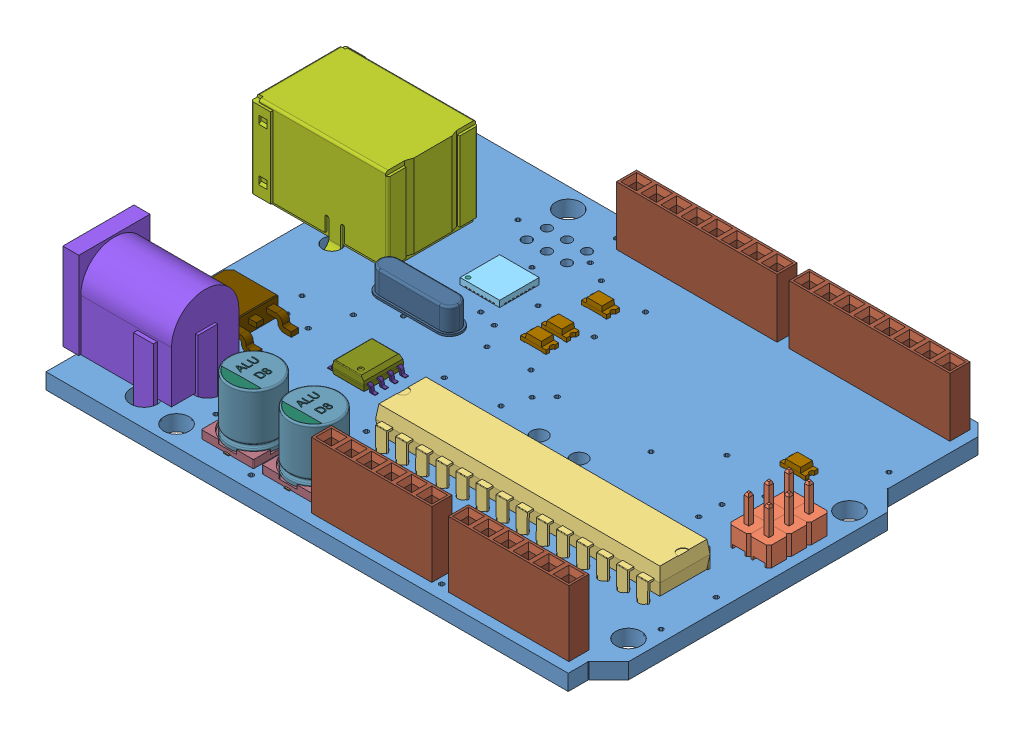
SolidWorks assembly Final, configuration Predeterminado. Lengths in mm.
Overall size (74.75 15.43 53.34).
32 component instances, 18 part files, 18 mates.
Components (placement in the parent):
- PCB_Final-1: PCB_Final [Default] at origin size (68.58 2 53.34)
- Header Vertical 2.54mm Pitch2-1: Header Vertical 2.54mm Pitch2 [Header 6 Way] at (62.2731 2 -29.1415) size (5.08 8.88 7.62)
- IC DIP 28-1: IC DIP 28 [Default] at (51.4233 4.3498 -16.4837) x (0 0.005002 0.999987) z (-1 0 0) size (7.87 6.22 35.94)
- User Library-QFN32 (FTDI)-1: User Library-QFN32 (FTDI) [Default] at (19.2089 2.05 -38.1588) x (-1 0 0) z (0 1 0) size (5 5 0.85)
  - User Library-QFN32 (FTDI)_Anschl_X_FCsse_1-1: User Library-QFN32 (FTDI)_Anschl_X_FCsse_1 [Default] x (0 -1 0) z (0 0 1) size (5 5 0.2)
  - User Library-QFN32 (FTDI)_K_X_F6rper_1-1: User Library-QFN32 (FTDI)_K_X_F6rper_1 [Default] at origin size (5 5 0.8)
  - User Library-QFN32 (FTDI)_Beschriftung_1-1: User Library-QFN32 (FTDI)_Beschriftung_1 [Default] at origin size (0.51 0.51 0.05)
- User Library-67068-0000-molex-1: User Library-67068-0000-molex [Default] at (-6.1546 2 -38.0545) x (0.002421 0 0.999997) z (-0.999997 0 0.002421) size (14.9 15.43 17)
- User Library-dc range - dc connector[4840_2201]-1: User Library-dc range - dc connector[4840_2201] [Default] at (11.794 2 -12.8354) x (0 0 1) z (-1 0 0) size (9.51 14.5 13.83)
- LED 1206-2: LED 1206 [Default] at (28.1068 2 -36.9237) x (0 0 -1) z (1 0 0) size (1.6 1.1 3.2)
- LED 1206-3: LED 1206 [Default] at (28.142 2 -34.2868) x (0 0 -1) z (1 0 0) size (1.6 1.1 3.2)
- LED 1206-4: LED 1206 [Default] at (58.3346 2 -36.8813) x (0 0 -1) z (1 0 0) size (1.6 1.1 3.2)
- LED 1206-5: LED 1206 [Default] at (28.1068 2 -41.994) x (0 0 -1) z (1 0 0) size (1.6 1.1 3.2)
- XTAL Small-1: XTAL Small [Default] at (14.2222 2 -30.4346) x (1 0 0) z (0 1 0) size (10.67 3.05 5.63)
- Stackable Female Pin Header-1: Stackable Female Pin Header [6 Way] at (50.8347 2 -2.5872) size (15.24 8.3 2.54)
- Stackable Female Pin Header-2: Stackable Female Pin Header [Default] at (45.7158 1.1368 -50.806) size (20.32 8.3 2.54)
- Stackable Female Pin Header-3: Stackable Female Pin Header [Default] at (23.9415 1.1201 -50.7298) size (20.32 8.3 2.54)
- Stackable Female Pin Header-4: Stackable Female Pin Header [6 Way] at (33.5006 2 -2.5872) size (15.24 8.3 2.54)
- User Library-ALU-D8-1: User Library-ALU-D8 [Default] at (20.4464 1.8 -5.7935) x (0 0 -1) z (0 1 0) size (7 6.6 7.71)
  - User Library-ALU-D8_Pins_1-1: User Library-ALU-D8_Pins_1 [Default] at origin size (7 0.65 0.4)
  - User Library-ALU-D8_Fuss_1-1: User Library-ALU-D8_Fuss_1 [Default] at origin size (6.6 6.6 1)
  - User Library-ALU-D8_K_X_F6rper_1-1: User Library-ALU-D8_K_X_F6rper_1 [Default] at origin size (6.3 6.3 7)
  - User Library-ALU-D8_Beschriftung_1-1: User Library-ALU-D8_Beschriftung_1 [Default] at origin size (4.36 4.98 0.11)
- User Library-ALU-D8-2: User Library-ALU-D8 [Default] at (28.1214 1.8 -5.7935) x (0 0 -1) z (0 1 0) size (7 6.6 7.71)
  - User Library-ALU-D8_Pins_1-1: User Library-ALU-D8_Pins_1 [Default] at origin size (7 0.65 0.4)
  - User Library-ALU-D8_Fuss_1-1: User Library-ALU-D8_Fuss_1 [Default] at origin size (6.6 6.6 1)
  - User Library-ALU-D8_K_X_F6rper_1-1: User Library-ALU-D8_K_X_F6rper_1 [Default] at origin size (6.3 6.3 7)
  - User Library-ALU-D8_Beschriftung_1-1: User Library-ALU-D8_Beschriftung_1 [Default] at origin size (4.36 4.98 0.11)
- User Library-SOIC-8-1: User Library-SOIC-8 [Default] at (20.4108 1.85 -20.3024) x (0 0 -1) z (1 0 0) size (5 1.75 6.01)
  - User Library-SOIC-8_SOIC-8_Body_1-1: User Library-SOIC-8_SOIC-8_Body_1 [Default] at origin size (5 1.6 4)
  - User Library-SOIC-8_SOIC-8_Pins_1-1: User Library-SOIC-8_SOIC-8_Pins_1 [Default] at origin size (4.23 0.99 6.01)
- SO 369A-1: SO 369A [Standard] at (5.5398 2 -17.4191) x (0 0 -1) z (0 1 0) size (6.6 10.1 2.4)
Mates (geometry in assembly coordinates):
- Coincidente1: coincident anti-aligned: plane of PCB_Final-1 through (-33.5843 2 -26.6884) normal (0 1 0); plane of Header Vertical 2.54mm Pitch2-1 through (63.8431 2 -27.8715) normal (0 -1 0)
- Coincidente2: coincident anti-aligned: plane of PCB_Final-1 through (-33.5843 2 -26.6884) normal (0 1 0); plane of User Library-QFN32 (FTDI)-1/User Library-QFN32 (FTDI)_Anschl_X_FCsse_1-1 through (19.2089 2 -38.1588) normal (0 -1 0)
- Coincidente3: coincident anti-aligned: plane of PCB_Final-1 through (-33.5843 2 -26.6884) normal (0 1 0); plane of User Library-67068-0000-molex-1 through (10.8308 2 -44.0956) normal (0 -1 0)
- Coincidente4: coincident anti-aligned: plane of PCB_Final-1 through (-33.5843 2 -26.6884) normal (0 1 0); plane of User Library-dc range - dc connector[4840_2201]-1 through (-1.706 2 -12.8354) normal (0 -1 0)
- Paralelo1: parallel: line of PCB_Final-1 through (66.04 2 0) axis (-1 0 0); plane of User Library-dc range - dc connector[4840_2201]-1 through (0.3218 7.6431 -4.0756) normal (0 0 1)
- Coincidente7: coincident anti-aligned: plane of PCB_Final-1 through (-33.5843 2 -26.6884) normal (0 1 0); plane of LED 1206-2 through (29.7068 2 -37.7237) normal (0 -1 0)
- Paralelo2: parallel anti-aligned: line of PCB_Final-1 through (0 2 0) axis (0 0 -1); line of LED 1206-2 through (29.7068 2.5 -36.5883) axis (0 0 1)
- Coincidente10: coincident anti-aligned: plane of PCB_Final-1 through (-33.5843 2 -26.6884) normal (0 1 0); plane of XTAL Small-1 through (11.6822 2 -31.7046) normal (0 -1 0)
- Coincidente11: coincident anti-aligned: plane of PCB_Final-1 through (-33.5843 2 -26.6884) normal (0 1 0); plane of Stackable Female Pin Header-1 through (49.5647 2 -1.3172) normal (0 -1 0)
- Coincidente12: coincident aligned: plane of Stackable Female Pin Header-1 through (52.1047 10.3 -1.3172) normal (0 0 1); plane of Stackable Female Pin Header-4 through (34.7706 10.3 -1.3172) normal (0 0 1)
- Coincidente14: coincident anti-aligned: plane of PCB_Final-1 through (-33.5843 2 -26.6884) normal (0 1 0); plane of Stackable Female Pin Header-4 through (32.2306 2 -1.3172) normal (0 -1 0)
- Coincidente19: coincident anti-aligned: plane of PCB_Final-1 through (-33.5843 2 -26.6884) normal (0 1 0); plane of User Library-ALU-D8-1/User Library-ALU-D8_Fuss_1-1 through (20.4464 2 -5.5067) normal (0 -1 0)
- Paralelo4: parallel anti-aligned: line of PCB_Final-1 through (66.04 2 0) axis (-1 0 0); line of User Library-ALU-D8-1/User Library-ALU-D8_Fuss_1-1 through (20.7964 2 -2.4935) axis (1 0 0)
- Coincidente21: coincident anti-aligned: plane of PCB_Final-1 through (-33.5843 2 -26.6884) normal (0 1 0); plane of User Library-SOIC-8-1/User Library-SOIC-8_SOIC-8_Body_1-1 through (20.4108 2 -20.3024) normal (0 -1 0)
- Paralelo5: parallel aligned: line of PCB_Final-1 through (66.04 2 0) axis (-1 0 0); line of User Library-SOIC-8-1/User Library-SOIC-8_SOIC-8_Body_1-1 through (22.346 2.0878 -17.8671) axis (-1 0 0)
- Paralelo6: parallel aligned: line of PCB_Final-1 through (0 2 0) axis (0 0 -1); line of User Library-QFN32 (FTDI)-1/User Library-QFN32 (FTDI)_K_X_F6rper_1-1 through (16.7089 2.85 -35.6588) axis (0 0 -1)
- Coincidente22: coincident anti-aligned: plane of PCB_Final-1 through (-33.5843 2 -26.6884) normal (0 1 0); plane of SO 369A-1 through (2.4398 2 -14.1191) normal (0 -1 0)
- Paralelo7: parallel aligned: line of PCB_Final-1 through (0 2 0) axis (0 0 -1); line of SO 369A-1 through (1.9398 2.6 -15.7191) axis (0 0 -1)
